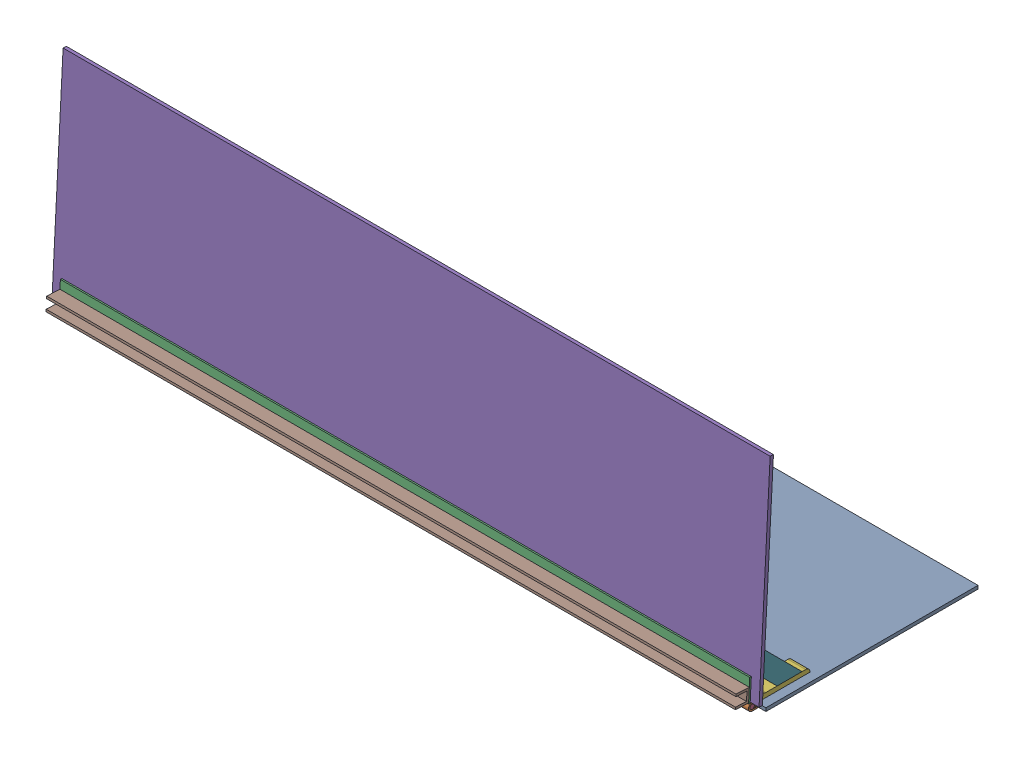
SolidWorks assembly FE-00014_ASM, configuration Default. Lengths in mm.
Overall size (1016 321.61 335.96).
9 component instances, 7 part files, 0 mates.
Components (placement in the parent):
- FE-00014-01-1: FE-00014-01 [Default] at origin size (1016 4.76 304.8)
- FE-00014-02_ASM-1: FE-00014-02_ASM [Default] at (0 -2.286 159.4485) x (1 0 0) z (0 -1 0) size (990.6 43.84 44.07)
  - FE-00014-02-A-1: FE-00014-02-A [Default] at origin size (990.6 43.56 10.92)
  - FE-00014-02-B-1: FE-00014-02-B [Default] at (0 5.4535 -5.7468) x (-1 0 0) z (0 0.99863 -0.052336) size (990.6 43.56 10.92)
  - FE-00014-02-C-1: FE-00014-02-C [Default] at (0 0 -5.461) size (990.6 6.35 6.35)
- FE-00014-01-2: FE-00014-01 [Default] at (0 162.5711 154.2743) x (1 0 0) z (0 0.99863 -0.052336) size (1016 4.76 304.8)
- FE-00014-04-1: FE-00014-04 [Default] at (482.6 4.7625 152.4) x (1 0 0) z (0 -1 0) size (25.4 76.2 76.2)
- FE-00014-05-1: FE-00014-05 [Default] at (495.3 40.2983 116.8642) x (0 0.707107 0.707107) z (0 0.707107 -0.707107) size (82.55 25.4 25.4)
- FE-00014-03-1: FE-00014-03 [Default] at (0 20.0116 164.0346) x (1 0 0) z (0 -0.052336 -0.99863) size (990.6 19.05 19.05)
